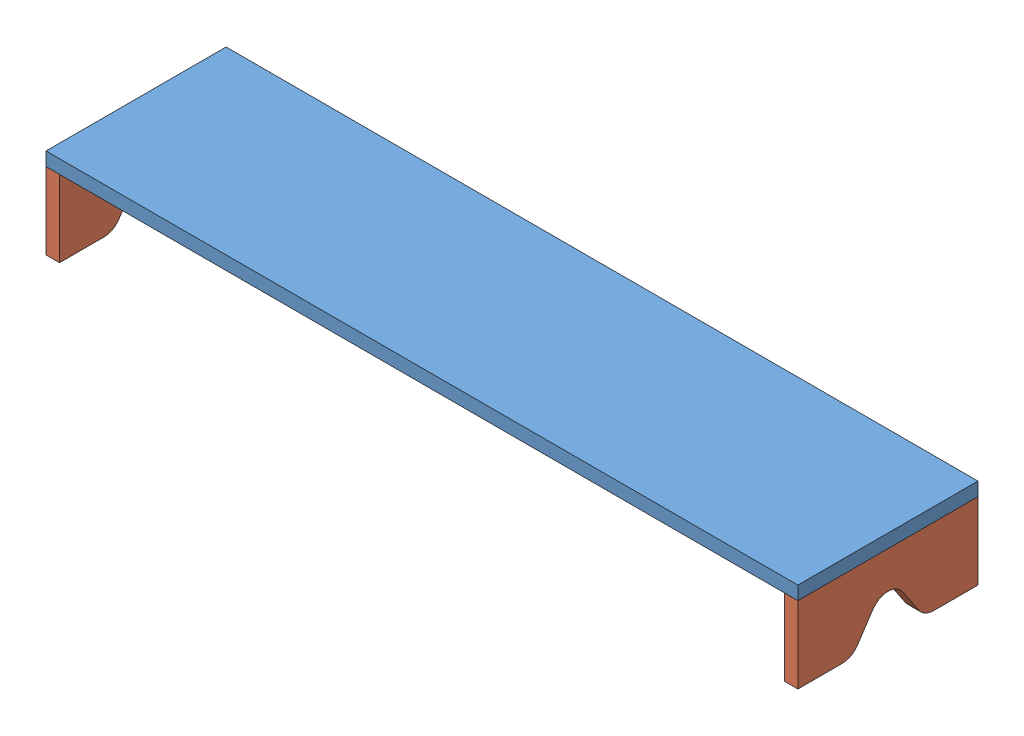
SolidWorks assembly Monitor Riser Assembly, configuration Just Riser. Lengths in mm.
Overall size (1060.45 127 254).
10 component instances, 9 part files, 29 mates.
Components (placement in the parent):
- Table-1: Table [Default] at (-40.2115 387.295 6.1571) size (1066.8 781.05 609.6) (suppressed, hidden)
- Asus Monitor-1: Asus Monitor [Default] at (117.6083 539.695 -193.8679) x (0.98857 0 0.150765) z (-0.150765 0 0.98857) size (508 373.49 203.2) (suppressed, hidden)
- Dell Monitor-1: Dell Monitor [Default] at (-427.6168 539.695 -170.6454) x (0.965926 0 -0.258819) z (0.258819 0 0.965926) size (508 377.3 152.4) (suppressed, hidden)
- Top Panel-1: Top Panel [Default] at (-40.2115 520.645 -168.4679) size (1060.45 19.05 254)
- Panel Side-2: Panel Side [Default] at (-570.4365 412.695 -168.4679) size (19.05 107.95 254)
- Panel Side-3: Panel Side [Default] at (490.0135 412.695 -168.4679) x (-1 0 0) z (0 0 -1) size (19.05 107.95 254)
- Light-1: Light [Default] at (420.1635 539.695 -193.8679) size (139.7 411.53 377.9) (suppressed, hidden)
- Panel Support-1: Panel Support [Default] at (-40.2115 412.695 -244.6679) x (0 0 1) z (-1 0 0) size (101.6 107.95 19.05)
- 1719A100_2-PRONG HOOK-1: 1719A100_2-PRONG HOOK [1719A1] at (-570.4365 515.3856 -83.5461) x (0 0 1) z (-1 0 0) size (31.75 54.56 75.92) (suppressed, hidden)
- 29905T310_LOAD-RATED SCREW-IN HOOK-1: 29905T310_LOAD-RATED SCREW-IN HOOK [29905T31] at (-560.9115 462.8059 -132.5997) x (0 0 1) z (-1 0 0) size (6.5 14.61 29.48) (suppressed, hidden)
Mates (geometry in assembly coordinates):
- Distance1: distance = 127 mm: plane of Dell Monitor-1 through (-603.4106 539.695 -219.2679) normal (0 -1 0); plane of Table-1 through (-40.2115 412.695 6.1571) normal (0 1 0)
- Coincident2: coincident aligned: plane of Table-1 through (-570.4365 412.695 -295.4679) normal (0 0 -1); plane of Dell Monitor-1
- Distance2: distance = 127 mm anti-aligned: plane of Table-1 through (-40.2115 412.695 6.1571) normal (0 1 0); plane of Asus Monitor-1 through (117.8715 539.695 -193.8679) normal (0 -1 0)
- Tangent1: tangent aligned: plane of Table-1 through (-570.4365 412.695 -295.4679) normal (0 0 -1); cylinder of Asus Monitor-1 through (117.6083 552.395 -193.8679) axis (0 -1 0) radius 101.6
- Coincident4: coincident anti-aligned: plane of Table-1 through (-40.2115 412.695 6.1571) normal (0 1 0); plane of Panel Side-2 through (-551.3865 412.695 -104.0742) normal (0 -1 0)
- Coincident5: coincident aligned: plane of Table-1 through (-570.4365 412.695 -295.4679) normal (0 0 -1); plane of Panel Side-2 through (-551.3865 520.645 -295.4679) normal (0 0 -1)
- Coincident6: coincident aligned: plane of Table-1 through (-570.4365 412.695 307.7821) normal (-1 0 0); plane of Panel Side-2 through (-570.4365 438.095 -232.8616) normal (-1 0 0)
- Coincident7: coincident anti-aligned: plane of Table-1 through (-40.2115 412.695 6.1571) normal (0 1 0); plane of Panel Side-3 through (470.9635 412.695 -232.8616) normal (0 -1 0)
- Coincident8: coincident aligned: plane of Panel Side-3 through (470.9635 412.695 -295.4679) normal (0 0 -1); plane of Table-1 through (-570.4365 412.695 -295.4679) normal (0 0 -1)
- Coincident9: coincident aligned: plane of Table-1 through (490.0135 412.695 307.7821) normal (1 0 0); plane of Panel Side-3 through (490.0135 438.095 -104.0742) normal (1 0 0)
- Coincident11: coincident anti-aligned: plane of Top Panel-1 through (-40.2115 520.645 -168.4679) normal (0 -1 0); plane of Panel Side-3 through (470.9635 520.645 -295.4679) normal (0 1 0)
- Coincident12: coincident aligned: plane of Top Panel-1 through (490.0135 539.695 -41.4679) normal (1 0 0); plane of Panel Side-3 through (490.0135 438.095 -104.0742) normal (1 0 0)
- Coincident13: coincident aligned: plane of Top Panel-1 through (-570.4365 539.695 -295.4679) normal (0 0 -1); plane of Panel Side-3 through (470.9635 412.695 -295.4679) normal (0 0 -1)
- Coincident14: coincident anti-aligned: plane of Asus Monitor-1 through (117.6083 539.695 -193.8679) normal (0 -1 0); plane of Top Panel-1 through (-40.2115 539.695 -168.4679) normal (0 1 0)
- Coincident16: coincident anti-aligned: plane of Dell Monitor-1 through (-427.6168 539.695 -170.6454) normal (0 -1 0); plane of Top Panel-1 through (-40.2115 539.695 -168.4679) normal (0 1 0)
- Angle1: planar angle = 0.261799 rad aligned: plane of Dell Monitor-1 through (-536.701 549.855 -62.5283) normal (0.258819 0 0.965926); plane of Top Panel-1 through (-570.4365 539.695 -41.4679) normal (0 0 1)
- Angle2: planar angle = 0.174533 rad aligned: plane of Asus Monitor-1 through (112.5194 542.6481 -160.4998) normal (-0.150192 0.087156 0.984808); plane of Top Panel-1 through (-570.4365 539.695 -41.4679) normal (0 0 1)
- Tangent3: tangent aligned: cylinder of Dell Monitor-1 through (-545.0365 549.855 -191.7749) axis (0 -1 0) radius 25.4; plane of Top Panel-1 through (-570.4365 539.695 -41.4679) normal (-1 0 0)
- Distance3: distance = 25.4 mm: point of Dell Monitor-1; line of Top Panel-1 through (490.0135 539.695 -295.4679) axis (-1 0 0)
- Distance4: distance = 44.45 mm: point of Dell Monitor-1; point of Asus Monitor-1
- Coincident23: coincident anti-aligned: plane of Top Panel-1 through (-40.2115 539.695 -168.4679) normal (0 1 0); plane of Light-1 through (420.1635 539.695 -193.8679) normal (0 -1 0)
- Coincident24: coincident aligned: plane of Top Panel-1 through (490.0135 539.695 -41.4679) normal (1 0 0); plane of Light-1 through (490.0135 549.855 -92.2679) normal (1 0 0)
- Coincident25: coincident aligned: plane of Top Panel-1 through (-570.4365 539.695 -295.4679) normal (0 0 -1); plane of Light-1 through (350.3135 549.855 -295.4679) normal (0 0 -1)
- Coincident27: coincident anti-aligned: plane of Top Panel-1 through (-40.2115 520.645 -168.4679) normal (0 -1 0); plane of Panel Support-1 through (-40.2115 520.645 -244.6679) normal (0 1 0)
- Width1: width anti-aligned: plane of Panel Side-2 through (-551.3865 438.095 -232.8616) normal (1 0 0); plane of Panel Side-3 through (470.9635 438.095 -104.0742) normal (-1 0 0); plane of Panel Support-1 through (-49.7365 520.645 -295.4679) normal (-1 0 0); plane of Panel Support-1 through (-30.6865 520.645 -295.4679) normal (1 0 0)
- Coincident28: coincident aligned: plane of Top Panel-1 through (-570.4365 539.695 -295.4679) normal (0 0 -1); plane of Panel Support-1 through (-49.7365 520.645 -295.4679) normal (0 0 -1)
- Coincident29: coincident anti-aligned: plane of Panel Side-2 through (-570.4365 438.095 -232.8616) normal (-1 0 0); plane of 1719A100_2-PRONG HOOK-1 through (-570.4365 499.5106 -83.5461) normal (1 0 0)
- Distance5: distance = 25.4 mm: point of 1719A100_2-PRONG HOOK-1; plane of Top Panel-1 through (-40.2115 539.695 -168.4679) normal (0 1 0)
- Coincident30: coincident anti-aligned: plane of Panel Side-2 through (-570.4365 438.095 -232.8616) normal (-1 0 0); plane of 29905T310_LOAD-RATED SCREW-IN HOOK-1 through (-570.4365 459.5547 -132.5997) normal (1 0 0)
